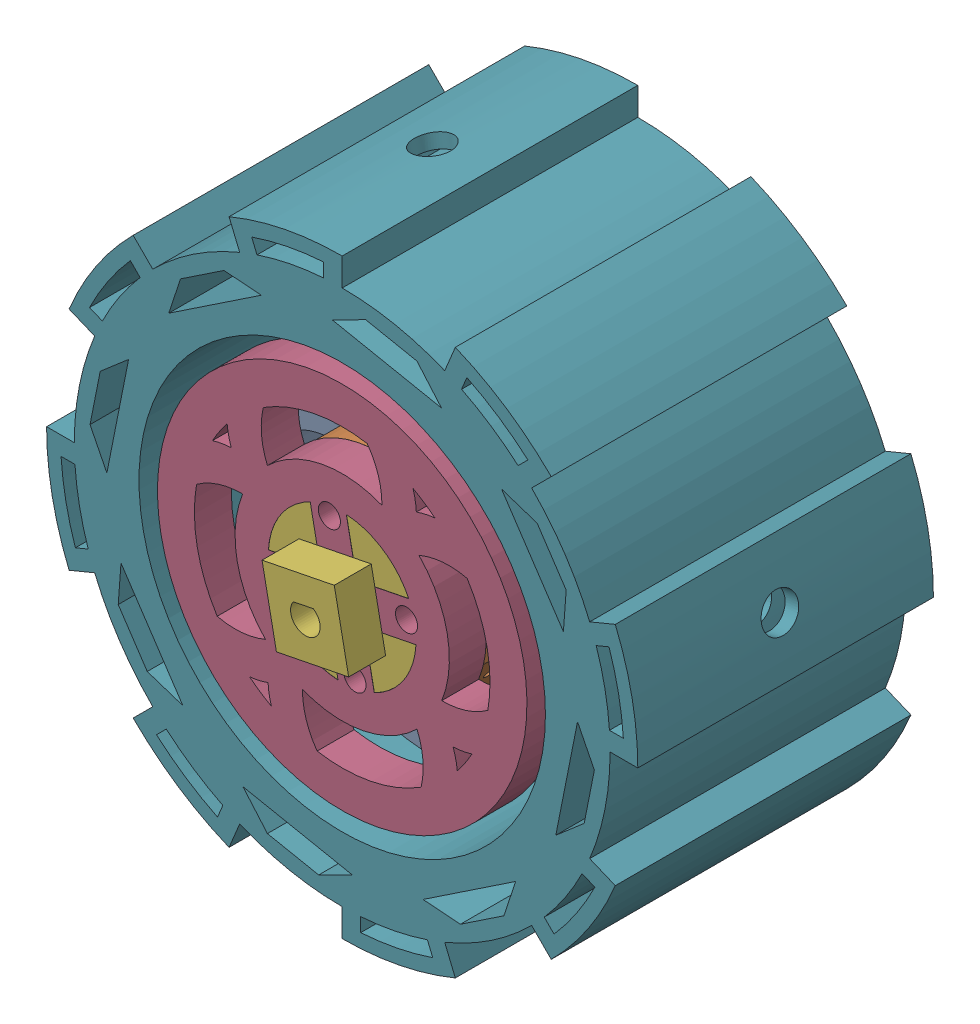
SolidWorks assembly Full_Wheel_Assembly_With_Connector, configuration Default. Lengths in mm.
Overall size (160 160 90).
7 component instances, 5 part files, 20 mates.
Components (placement in the parent):
- Inner Ring Design-1: Inner Ring Design [Default] at (2.0234 14.792 3.8828) x (0.980785 0.19509 0) z (0 0 1) size (100 100 30)
- Motor_Connector_Ring-1: Motor_Connector_Ring [Default] at (2.0234 14.792 18.8828) x (0.980785 0.19509 0) z (0 0 1) size (58 58 15)
- Motor_Connector_Ring-2: Motor_Connector_Ring [Default] at (2.0234 14.792 -26.1172) x (0.980785 0.19509 0) z (0 0 1) size (58 58 15)
- Outer Ring Design-1: Outer Ring Design [Default] at (2.0234 14.792 28.8828) x (0.980785 0.19509 0) z (0 0 1) size (100 100 10)
- Outer Ring Design-2: Outer Ring Design [Default] at (2.0234 14.792 -41.1172) x (0.980785 0.19509 0) z (0 0 1) size (100 100 10)
- Wheel_Brushing_Connector-1: Wheel_Brushing_Connector [Default] at (2.0509 14.8333 -51.1172) x (0 0 1) z (-0.980785 -0.19509 0) size (90 38.73 38.73)
- Wheel Design-2: Wheel Design [Default] at (2.0234 14.792 -51.1172) size (160 160 80)
Mates (geometry in assembly coordinates):
- Distance1: distance = 25 mm aligned: plane of Inner Ring Design-1 through (2.0234 14.792 3.8828) normal (0 0 1); plane of Wheel Design-1 through (2.0234 14.792 28.8828) normal (0 0 1)
- Concentric3: concentric anti-aligned: cylinder of Wheel Design-1 through (2.0234 14.792 95.8828) axis (0 0 -1) radius 55; cylinder of Inner Ring Design-1 through (2.0234 14.792 -26.1172) axis (0 0 1) radius 50
- Parallel5: parallel aligned: cylinder of Wheel Design-1 through (-105.863 -6.6679 -11.1172) axis (0.980785 0.19509 0) radius 1.5; cylinder of Inner Ring Design-1 through (34.3893 21.23 -11.1172) axis (0.980785 0.19509 0) radius 1.5
- Coincident5: coincident anti-aligned: plane of Inner Ring Design-1 through (2.0234 14.792 3.8828) normal (0 0 1); plane of Motor_Connector_Ring-1 through (2.0234 14.792 3.8828) normal (0 0 -1)
- Concentric5: concentric anti-aligned: cylinder of Inner Ring Design-1 through (-1.4395 32.201 30.8828) axis (0 0 -1) radius 2.987; cylinder of Motor_Connector_Ring-1 through (-1.4395 32.201 -51.1172) axis (0 0 1) radius 3.15
- Coincident6: coincident aligned: plane of Inner Ring Design-1 through (11.8312 16.7429 -26.1172) normal (-0.980785 -0.19509 0); plane of Motor_Connector_Ring-1 through (11.8312 16.7429 3.8828) normal (-0.980785 -0.19509 0)
- Coincident7: coincident anti-aligned: plane of Inner Ring Design-1 through (2.0234 14.792 -26.1172) normal (0 0 -1); plane of Motor_Connector_Ring-2 through (2.0234 14.792 -26.1172) normal (0 0 1)
- Concentric6: concentric anti-aligned: cylinder of Inner Ring Design-1 through (19.4323 18.2549 30.8828) axis (0 0 -1) radius 2.987; cylinder of Motor_Connector_Ring-2 through (19.4323 18.2549 -96.1172) axis (0 0 1) radius 3.15
- Coincident8: coincident aligned: plane of Inner Ring Design-1 through (11.8312 16.7429 -26.1172) normal (-0.980785 -0.19509 0); plane of Motor_Connector_Ring-2 through (11.8312 16.7429 -41.1172) normal (-0.980785 -0.19509 0)
- Coincident9: coincident anti-aligned: plane of Motor_Connector_Ring-1 through (2.0234 14.792 18.8828) normal (0 0 1); plane of Outer Ring Design-1 through (2.0234 14.792 18.8828) normal (0 0 -1)
- Concentric7: concentric aligned: cylinder of Motor_Connector_Ring-1 through (19.4323 18.2549 -51.1172) axis (0 0 1) radius 3.15; cylinder of Outer Ring Design-1 through (19.4323 18.2549 18.8828) axis (0 0 1) radius 2.987
- Coincident10: coincident aligned: plane of Motor_Connector_Ring-1 through (11.8312 16.7429 3.8828) normal (-0.980785 -0.19509 0); plane of Outer Ring Design-1 through (11.8312 16.7429 18.8828) normal (-0.980785 -0.19509 0)
- Coincident12: coincident anti-aligned: plane of Motor_Connector_Ring-2 through (2.0234 14.792 -41.1172) normal (0 0 -1); plane of Outer Ring Design-2 through (2.0234 14.792 -41.1172) normal (0 0 1)
- Concentric8: concentric aligned: cylinder of Motor_Connector_Ring-2 through (-1.4395 32.201 -96.1172) axis (0 0 1) radius 3.15; cylinder of Outer Ring Design-2 through (-1.4395 32.201 -51.1172) axis (0 0 1) radius 2.987
- Coincident13: coincident aligned: plane of Motor_Connector_Ring-2 through (11.8312 16.7429 -41.1172) normal (-0.980785 -0.19509 0); plane of Outer Ring Design-2 through (11.8312 16.7429 -51.1172) normal (-0.980785 -0.19509 0)
- Coincident16: coincident anti-aligned: plane of Outer Ring Design-2 through (0.0725 24.5999 -51.1172) normal (0.19509 -0.980785 0); plane of Wheel_Brushing_Connector-1 through (0.1069 24.6067 38.8828) normal (-0.19509 0.980785 0)
- Coincident17: coincident aligned: plane of Outer Ring Design-2 through (2.0234 14.792 -51.1172) normal (0 0 -1); plane of Wheel_Brushing_Connector-1 through (2.0509 14.8333 -51.1172) normal (0 0 -1)
- Concentric11: concentric anti-aligned: cylinder of Inner Ring Design-1 through (2.0234 14.792 -26.1172) axis (0 0 1) radius 50; cylinder of Wheel Design-2 through (2.0234 14.792 95.8828) axis (0 0 -1) radius 55
- Coincident18: coincident aligned: plane of Outer Ring Design-2 through (2.0234 14.792 -51.1172) normal (0 0 -1); plane of Wheel Design-2 through (2.0234 14.792 -51.1172) normal (0 0 -1)
- Concentric12: concentric aligned: cylinder of Inner Ring Design-1 through (34.3893 21.23 -11.1172) axis (0.980785 0.19509 0) radius 1.5; cylinder of Wheel Design-2 through (-105.863 -6.6679 -11.1172) axis (0.980785 0.19509 0) radius 1.5
